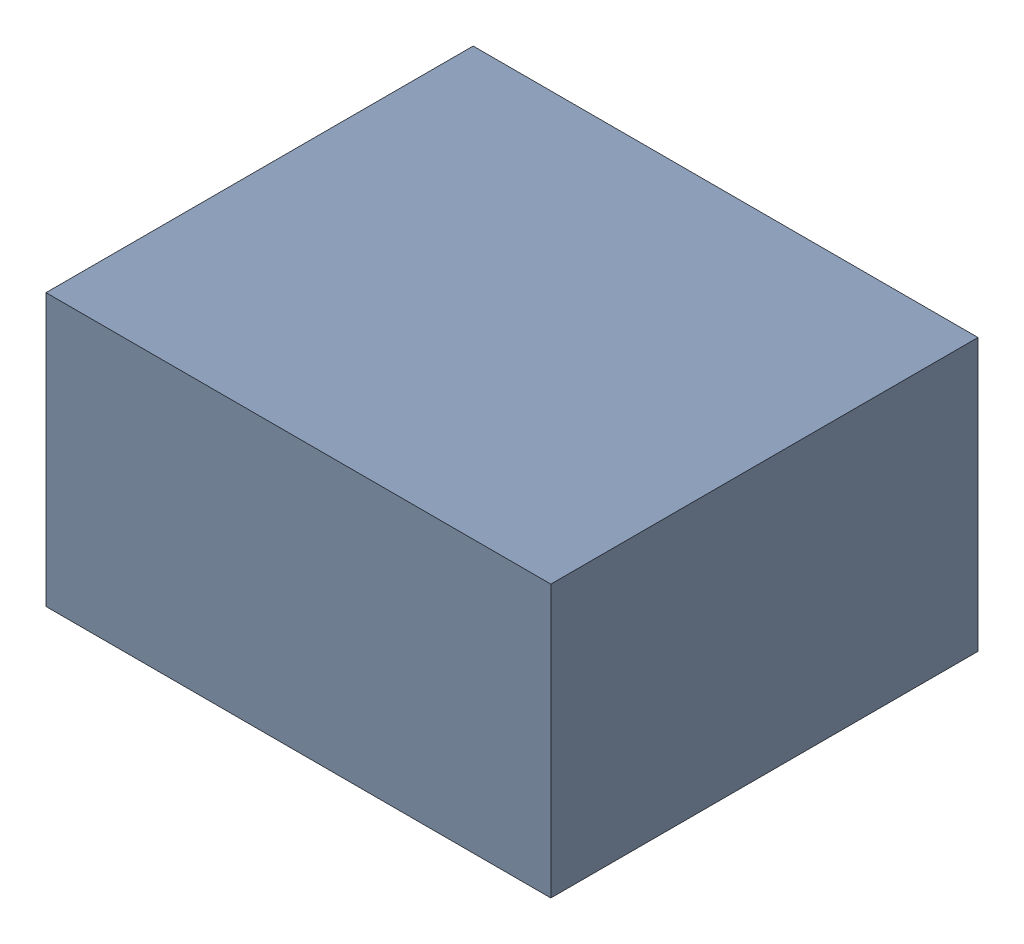
SolidWorks assembly L201, configuration Standard. Lengths in mm.
Overall size (0.65 0.35 0.55).
2 component instances, 1 part files, 0 mates.
Components (placement in the parent):
- 885541696-1: 885541696 [Standard] at (16.14 10.01 0) size (0.65 0.35 0.55)
  - Extruded_32-1: Extruded_32 [Standard] at origin size (0.65 0.35 0.55)
